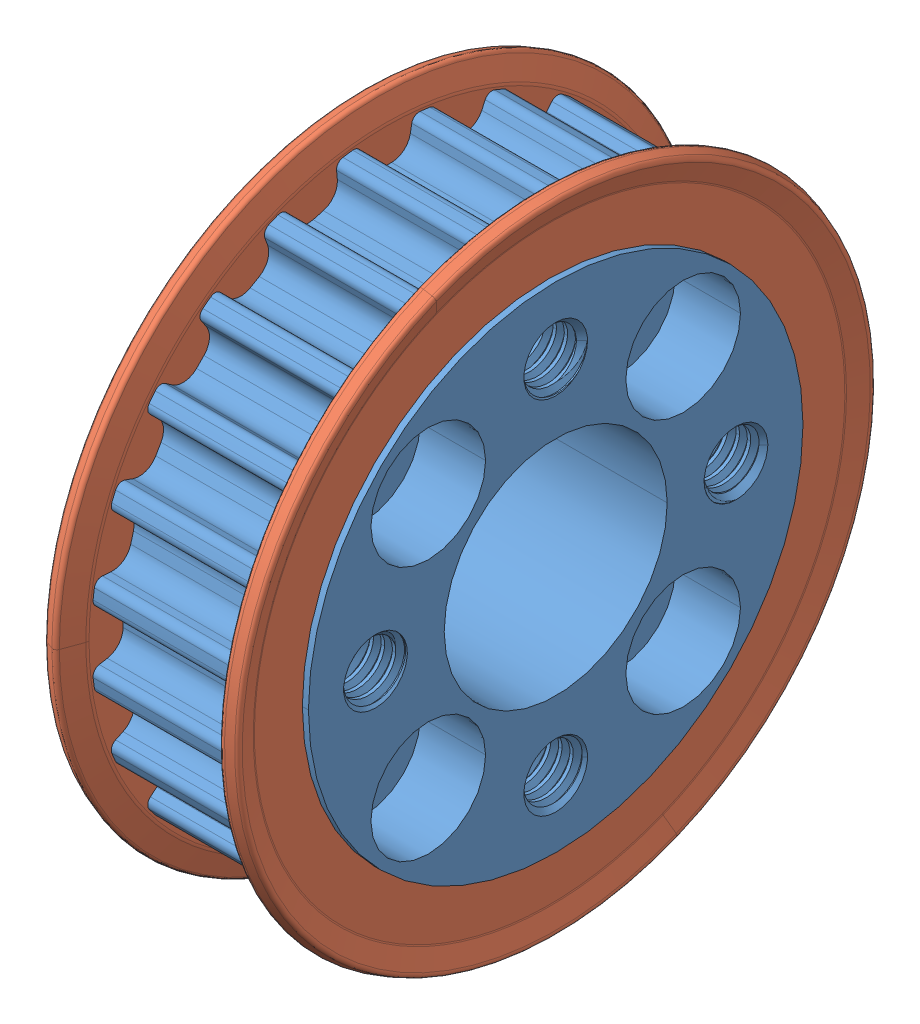
SolidWorks assembly 3411-0014-0024 Assembly, configuration Default. Lengths in mm.
Overall size (12.11 52.82 52.82).
4 component instances, 2 part files, 0 mates.
Components (placement in the parent):
- 3411-0014-0024 Assembly.STEP-1: 3411-0014-0024 Assembly.STEP [Default] at origin size (12.11 52.82 52.82)
  - 3411-0014-0024 Body.STEP-1: 3411-0014-0024 Body.STEP [Default] at (-9.2805 19.7149 33.0416) size (12.02 36.82 36.82)
  - 3411-0014-0024 Ring.STEP-1: 3411-0014-0024 Ring.STEP [Default] at (-0.5737 19.7149 33.0416) x (0 1 0) z (0 0 1) size (40.44 1.43 40.44)
  - 3411-0014-0024 Ring.STEP-2: 3411-0014-0024 Ring.STEP [Default] at (8.6763 19.7149 33.0416) x (0 0.381849 -0.924225) z (0 -0.924225 -0.381849) size (40.44 1.43 40.44)
